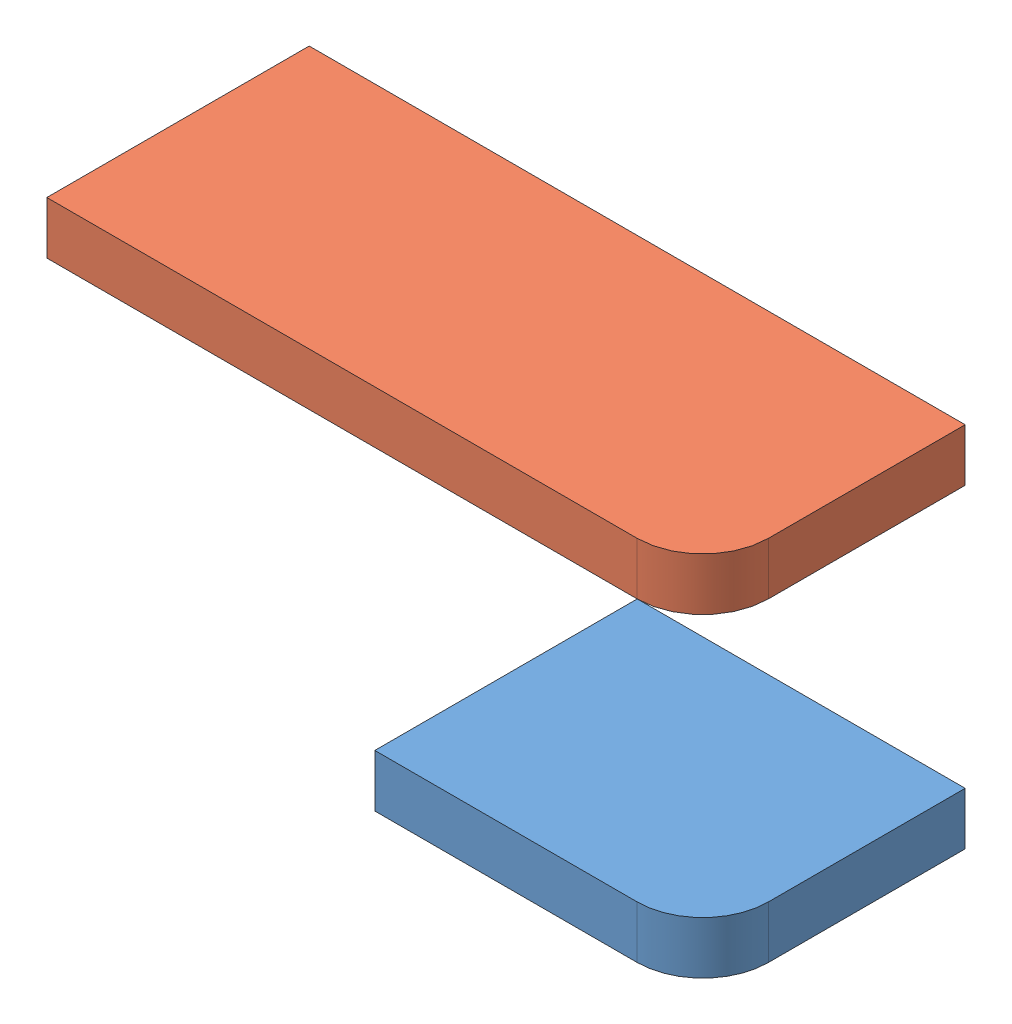
SolidWorks assembly carriage_axis_y_console_left, configuration По умолчанию. Lengths in mm.
Overall size (100 56 43).
3 component instances, 3 part files, 7 mates.
Components (placement in the parent):
- carriage_axis_y_console_plywood_left-1: carriage_axis_y_console_plywood_left [По умолчанию] at (-26.0552 4.4348 42.4071) size (50 8 43)
- carriage_axis_y_console_plywood_left_top-1: carriage_axis_y_console_plywood_left_top [По умолчанию] at (-51.0552 52.4348 42.4071) size (100 8 43)
- carriage_axis_y_console_adge_plywood_left-1: carriage_axis_y_console_adge_plywood_left [По умолчанию] at (-51.0552 4.4348 42.4071) x (0 0 1) z (-1 0 0) size (43 48 6)
Mates (geometry in assembly coordinates):
- Совпадение1: coincident aligned: plane of carriage_axis_y_console_plywood_left-1 through (-1.0552 12.4348 53.9071) normal (1 0 0); plane of carriage_axis_y_console_plywood_left_top-1 through (-1.0552 60.4348 53.9071) normal (1 0 0)
- Совпадение3: coincident aligned: plane of carriage_axis_y_console_plywood_left-1 through (-51.0552 12.4348 20.9071) normal (0 0 -1); plane of carriage_axis_y_console_plywood_left_top-1 through (-101.0552 60.4348 20.9071) normal (0 0 -1)
- Расстояние1: distance = 40 mm anti-aligned: plane of carriage_axis_y_console_plywood_left-1 through (-11.0552 12.4348 53.9071) normal (0 1 0); plane of carriage_axis_y_console_plywood_left_top-1 through (-11.0552 52.4348 53.9071) normal (0 -1 0)
- На месте1: in place: plane of carriage_axis_y_console_plywood_left-1 through (-51.0552 12.4348 62.4071) normal (-1 0 0); plane of ? through (-51.0552 0 0) normal (-1 0 0); moOrthogonalPlaneRef_w of carriage_axis_y_console_plywood_left-1 through (-51.0552 12.4348 62.4071) normal (-1 0 0); plane of ? through (-51.0552 0 0) normal (0 1 0); plane of carriage_axis_y_console_plywood_left-1 through (-51.0552 12.4348 62.4071) normal (-1 0 0); plane of ? through (-51.0552 0 0) normal (0 0 1); plane of carriage_axis_y_console_plywood_left-1 through (-51.0552 12.4348 63.9071) normal (-1 0 0); unknown of carriage_axis_y_console_adge_plywood_left-1
- Совпадение6: coincident aligned: plane of ?; plane of ?
- Совпадение7: coincident aligned: moOrthogonalPlaneRef_w of carriage_axis_y_console_plywood_left-1 through (-51.0552 4.4348 42.4071) normal (0 1 0); plane of Деталь1^carriage_axis_y_console_left-1 through (-51.0552 4.4348 42.4071) normal (0 1 0)
- Совпадение8: coincident anti-aligned: moOrthogonalPlaneRef_w of carriage_axis_y_console_plywood_left-1 through (-51.0552 4.4348 42.4071) normal (0 0 -1); plane of Деталь1^carriage_axis_y_console_left-1 through (-51.0552 4.4348 42.4071) normal (0 0 1)
